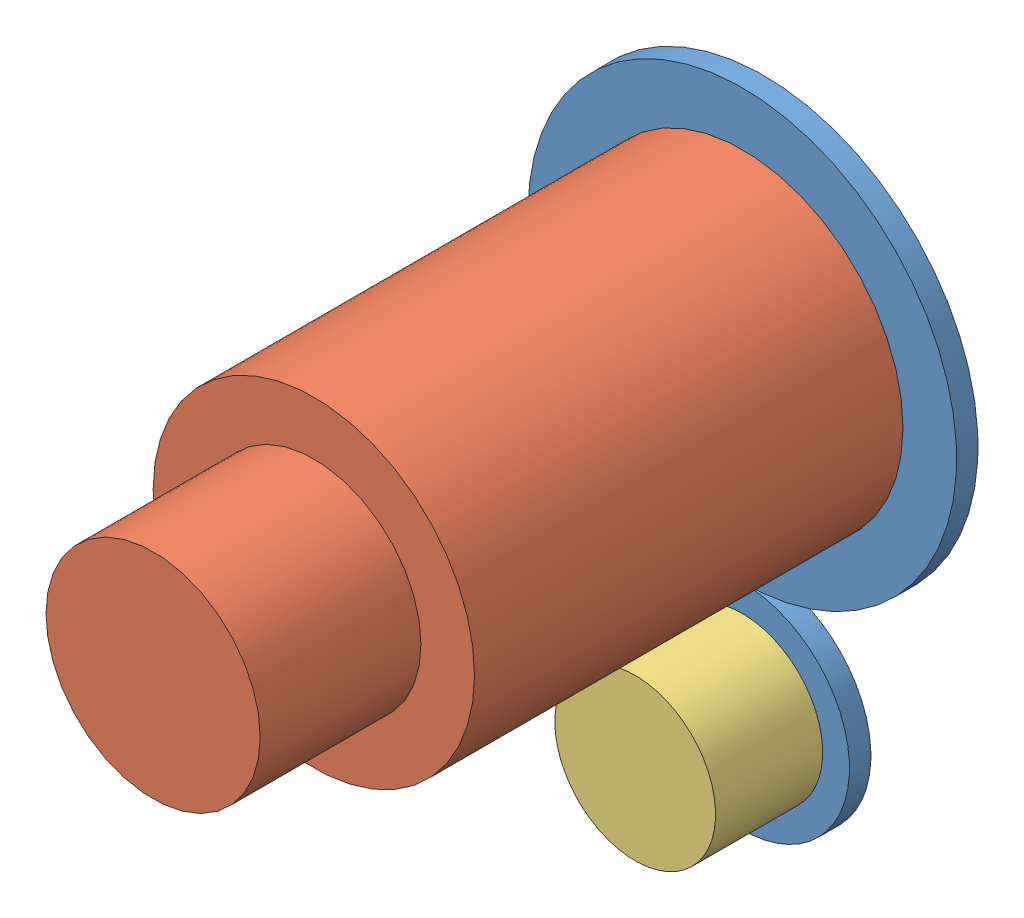
SolidWorks assembly 004-Git Hub test ASY, configuration Default. Lengths in mm.
Overall size (50.8 76.2 72.39).
3 component instances, 3 part files, 4 mates.
Components (placement in the parent):
- 002-Github test base-1: 002-Github test base [Default] at origin size (50.8 76.2 2.54)
- 003-Github test top-1: 003-Github test top [Default] at (0 0 2.54) size (50.8 76.2 69.85)
- 005-Github Test front-1: 005-Github Test front [Default] at (0 0 2.54) size (50.8 76.2 12.7)
Mates (geometry in assembly coordinates):
- Coincident1: coincident anti-aligned: plane of 002-Github test base-1 through (0 0 2.54) normal (0 0 1); plane of 003-Github test top-1 through (0 38.1 2.54) normal (0 0 -1)
- Coincident2: coincident aligned: circle of 002-Github test base-1; circle of 003-Github test top-1
- Coincident3: coincident: plane of 002-Github test base-1 through (0 0 2.54) normal (0 0 1); plane of 005-Github Test front-1 through (0 0 2.54) normal (0 0 -1)
- Concentric1: concentric aligned: cylinder of 002-Github test base-1 through (0 0 2.54) axis (0 0 -1) radius 12.7; cylinder of 005-Github Test front-1 through (0 0 15.24) axis (0 0 -1) radius 9.525
